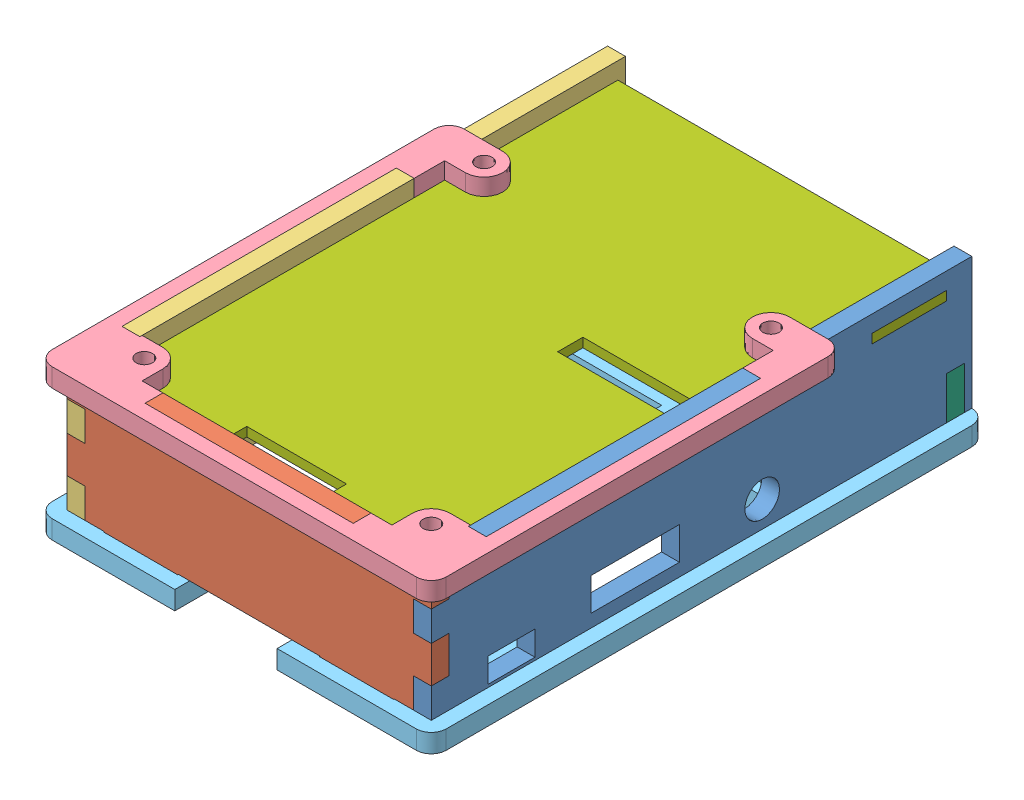
SolidWorks assembly ai_Enclosure_rpib+_Hat, configuration Default. Lengths in mm.
Overall size (67.31 25.65 94.89).
8 component instances, 8 part files, 24 mates.
Components (placement in the parent):
- ai_enc_rpib+_right_panel-1: ai_enc_rpib+_right_panel [Default] at (19.0331 -24.1776 39.8289) size (3.05 25.65 92.35)
- ai_enc_rpib+_back_panel-1: ai_enc_rpib+_back_panel [Default] at (19.0331 -24.1776 39.8289) size (62.23 25.53 3.05)
- ai_enc_rpib+_left_panel-1: ai_enc_rpib+_left_panel [Default] at (-37.1009 -24.1776 39.8289) x (0 0 1) z (-1 0 0) size (92.35 25.65 3.05)
- ai_enc_rpib+_top_panel-1: ai_enc_rpib+_top_panel [Default] at (19.0331 -0.1492 39.8289) x (1 0 0) z (0 1 0) size (67.31 70.36 3.17)
- ai_enc_rpib+_bottom_panel-1: ai_enc_rpib+_bottom_panel [Default] at (19.0331 -19.4532 39.8289) x (-1 0 0) z (0 -1 0) size (67.31 94.89 3.17)
- Part9^ai_Enclosure_rpib+_Hat-1: Part9^ai_Enclosure_rpib+_Hat [Default] at origin (virtual)
- ai_enc_rpib+_front_panel-1: ai_enc_rpib+_front_panel [Default] at (19.0331 -24.1776 -45.1341) x (-1 0 0) z (0 0 -1) size (62.23 20.98 3.05)
- ai_enc_rpib+_hood_panel-1: ai_enc_rpib+_hood_panel [Default] at (19.0331 -1.4192 39.8289) x (1 0 0) z (0 1 0) size (62.23 88.01 1.57)
Mates (geometry in assembly coordinates):
- InPlace4: in place: plane of ? through (20.8365 -24.1776 39.8289) normal (0 0 1); plane of ? through (0 0 39.8289) normal (0 0 1); moOrthogonalPlaneRef_w of ? through (20.8365 -24.1776 39.8289) normal (0 0 1); plane of ? through (0 0 39.8289) normal (0 1 0); plane of ? through (20.8365 -24.1776 39.8289) normal (0 0 1); plane of ? through (0 0 39.8289) normal (1 0 0); plane of ? through (22.0811 -24.1776 39.8289) normal (0 0 1); unknown of ?
- Coincident10: coincident aligned: plane of ai_enc_rpib+_right_panel-1; plane of ai_enc_rpib+_back_panel-1
- Coincident11: coincident aligned: moOrthogonalPlaneRef_w of ai_enc_rpib+_right_panel-1 through (19.0331 -24.1776 39.8289) normal (0 1 0); plane of ai_enc_rpib+_back_panel-1 through (19.0331 -24.1776 39.8289) normal (0 1 0)
- Coincident12: coincident anti-aligned: moOrthogonalPlaneRef_w of ai_enc_rpib+_right_panel-1 through (19.0331 -24.1776 39.8289) normal (-1 0 0); plane of ai_enc_rpib+_back_panel-1 through (19.0331 -24.1776 39.8289) normal (1 0 0)
- InPlace5: in place: plane of ? through (-37.1009 -2.9432 41.6323) normal (-1 0 0); plane of ? through (-37.1009 0 0) normal (-1 0 0); plane of ? through (-37.1009 -2.9432 41.6323) normal (-1 0 0); line of ? through (-55 -37.1009 0) axis (0 0 1); plane of ? through (-37.1009 -2.9432 41.6323) normal (-1 0 0); plane of ? through (-37.1009 0 0) normal (0 0 1); plane of ? through (-37.1009 -2.994 42.8769) normal (-1 0 0); unknown of ai_enc_rpib+_left_panel-1
- Coincident13: coincident aligned: plane of ai_enc_rpib+_back_panel-1; plane of ai_enc_rpib+_left_panel-1
- Coincident14: coincident aligned: moOrthogonalPlaneRef_w of ai_enc_rpib+_back_panel-1 through (-37.1009 -24.1776 39.8289) normal (0 1 0); plane of ai_enc_rpib+_left_panel-1
- Coincident15: coincident anti-aligned: moOrthogonalPlaneRef_w of ai_enc_rpib+_back_panel-1 through (-37.1009 -24.1776 39.8289) normal (0 0 -1); plane of ai_enc_rpib+_left_panel-1 through (-37.1009 -24.1776 39.8289) normal (0 0 1)
- InPlace6: in place: plane of ? through (20.8365 -0.0984 39.8289) normal (0 1 0); plane of ? through (0 -0.0984 0) normal (0 1 0); plane of ? through (20.8365 -0.0984 39.8289) normal (0 1 0); plane of ? through (0 -0.0984 0) normal (0 0 -1); plane of ? through (20.8365 -0.0984 39.8289) normal (0 1 0); line of ? through (-55 0 -0.0984) axis (0 1 0); plane of ? through (22.0811 -0.1492 39.8289) normal (0 1 0); unknown of ai_enc_rpib+_top_panel-1
- Coincident16: coincident aligned: plane of ai_enc_rpib+_right_panel-1; plane of ai_enc_rpib+_top_panel-1
- Coincident17: coincident aligned: moOrthogonalPlaneRef_w of ai_enc_rpib+_right_panel-1 through (19.0331 -0.1492 39.8289) normal (0 0 -1); plane of ai_enc_rpib+_top_panel-1 through (19.0331 -0.1492 39.8289) normal (0 0 -1)
- Coincident18: coincident anti-aligned: moOrthogonalPlaneRef_w of ai_enc_rpib+_right_panel-1 through (19.0331 -0.1492 39.8289) normal (-1 0 0); plane of ai_enc_rpib+_top_panel-1
- InPlace7: in place: plane of ? through (20.8365 -19.4532 39.8289) normal (0 -1 0); plane of ? through (0 -19.4532 0) normal (0 -1 0); plane of ? through (20.8365 -19.4532 39.8289) normal (0 -1 0); unknown of ?; plane of ? through (20.8365 -19.4532 39.8289) normal (0 -1 0); line of ? through (-55 0 -19.4532) axis (0 -1 0); plane of ? through (22.0811 -19.4532 39.8289) normal (0 -1 0); unknown of ai_enc_rpib+_bottom_panel-1
- Coincident19: coincident aligned: plane of ai_enc_rpib+_right_panel-1; plane of ai_enc_rpib+_bottom_panel-1
- Coincident20: coincident aligned: moOrthogonalPlaneRef_w of ai_enc_rpib+_right_panel-1 through (19.0331 -19.4532 39.8289) normal (0 0 -1); plane of ai_enc_rpib+_bottom_panel-1
- Coincident21: coincident anti-aligned: moOrthogonalPlaneRef_w of ai_enc_rpib+_right_panel-1 through (19.0331 -19.4532 39.8289) normal (1 0 0); plane of ai_enc_rpib+_bottom_panel-1
- InPlace8: in place: plane of ? through (20.8365 -24.1776 -45.1341) normal (0 0 -1); plane of ? through (0 0 -45.1341) normal (0 0 -1); plane of ? through (20.8365 -24.1776 -45.1341) normal (0 0 -1); unknown of ?; plane of ? through (20.8365 -24.1776 -45.1341) normal (0 0 -1); plane of ? through (0 0 -45.1341) normal (-1 0 0); plane of ? through (22.0811 -24.1776 -45.1341) normal (0 0 -1); unknown of ai_enc_rpib+_front_panel-1
- Coincident22: coincident aligned: plane of ai_enc_rpib+_right_panel-1; plane of ai_enc_rpib+_front_panel-1
- Coincident23: coincident aligned: moOrthogonalPlaneRef_w of ai_enc_rpib+_right_panel-1 through (19.0331 -24.1776 -45.1341) normal (0 1 0); plane of ai_enc_rpib+_front_panel-1
- Coincident24: coincident anti-aligned: moOrthogonalPlaneRef_w of ai_enc_rpib+_right_panel-1 through (19.0331 -24.1776 -45.1341) normal (1 0 0); plane of ai_enc_rpib+_front_panel-1 through (19.0331 -24.1776 -45.1341) normal (-1 0 0)
- InPlace9: in place: plane of ? through (20.8365 -1.4192 39.8289) normal (0 1 0); plane of ? through (0 -1.4192 0) normal (0 1 0); plane of ? through (20.8365 -1.4192 39.8289) normal (0 1 0); plane of ? through (0 -1.4192 0) normal (0 0 -1); plane of ? through (20.8365 -1.4192 39.8289) normal (0 1 0); line of ? through (-55 0 -1.4192) axis (0 1 0); plane of ? through (22.0811 -1.4192 39.8289) normal (0 1 0); unknown of ai_enc_rpib+_hood_panel-1
- Coincident1: coincident aligned: plane of ai_enc_rpib+_right_panel-1; plane of ai_enc_rpib+_hood_panel-1
- Coincident2: coincident aligned: moOrthogonalPlaneRef_w of ai_enc_rpib+_right_panel-1 through (19.0331 -1.4192 39.8289) normal (0 0 -1); plane of ai_enc_rpib+_hood_panel-1 through (19.0331 -1.4192 39.8289) normal (0 0 -1)
- Coincident3: coincident anti-aligned: moOrthogonalPlaneRef_w of ai_enc_rpib+_right_panel-1 through (19.0331 -1.4192 39.8289) normal (-1 0 0); plane of ai_enc_rpib+_hood_panel-1
